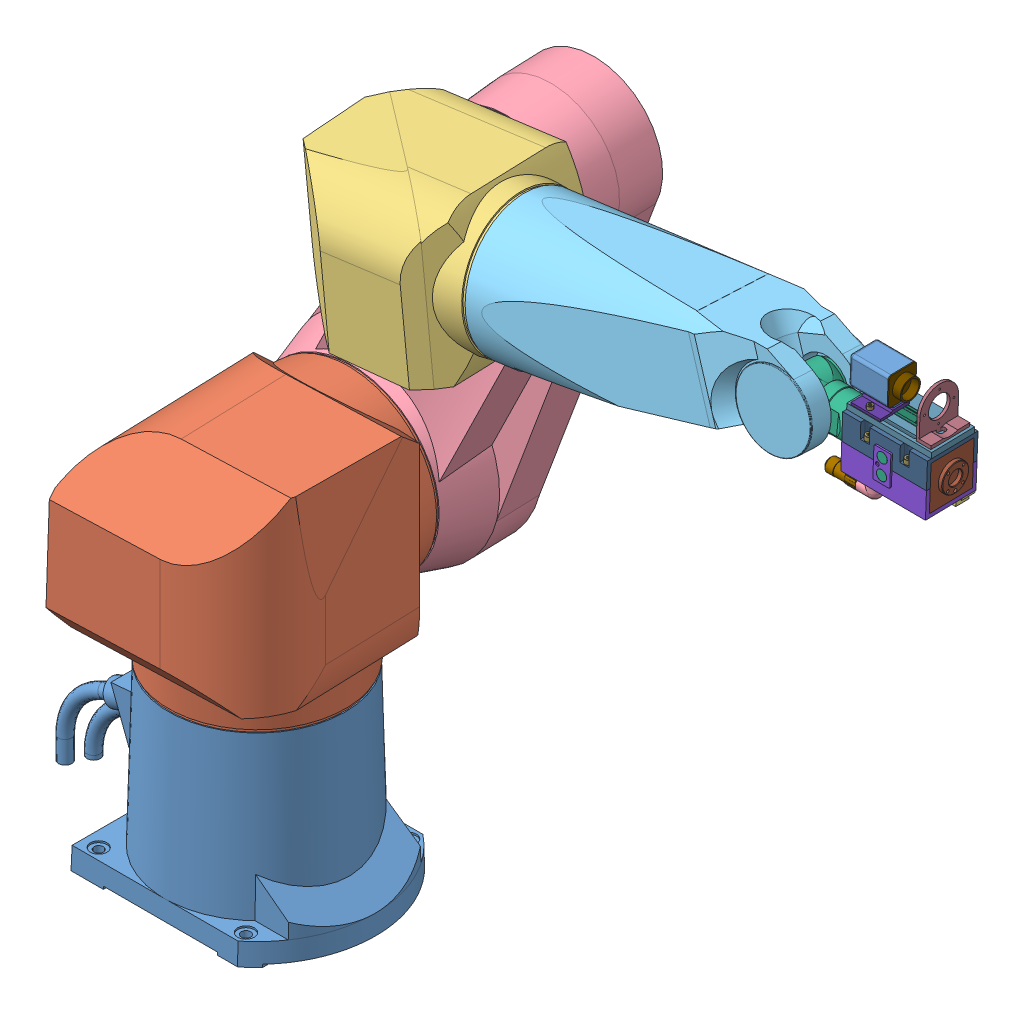
SolidWorks assembly Robot, configuration Default. Lengths in mm.
Overall size (1597.98 1325.39 584.25).
48 component instances, 29 part files, 15 mates.
Components (placement in the parent):
- _MASTER7-1: _MASTER7 [Default] at (48.6878 -5 -52.6772) x (1 0 0) z (0 1 0) size (596.97 337.24 339.66)
- _MASTER6-1: _MASTER6 [Default] at (48.6878 -5.8 -52.6772) x (0.999415 0 -0.034189) z (0 1 0) size (352.5 381 395)
- _MASTER4-1: _MASTER4 [Default] at (358.5721 1107.2932 1073.4366) x (-0.102425 0.994735 0.003504) z (-0.034189 0 -0.999415) size (263.05 319.02 284.97)
- _MASTER3-1: _MASTER3 [Default] at (-189.8314 48.678 -44.5178) x (0.900422 -0.433925 -0.030802) z (0.433671 0.900949 -0.014835) size (372 188.37 936)
- _MASTER-1: _MASTER [Default] at (-811.7526 990.7889 -62.2156) x (0.104669 -0.99202 0.070284) z (0.994153 0.102484 -0.034009) size (240 240 558.7)
- _MASTER1-1: _MASTER1 [Default] at (-820.8951 1231.1583 -80.4296) x (-0.029205 -0.996816 0.0742) z (0.999221 -0.031085 -0.024305) size (96.76 76.5 130.75)
- _MASTER2-1: _MASTER2 [Default] at (-821.8943 1231.1894 -80.4053) x (-0.015425 -0.874658 0.484495) z (0.999221 -0.031085 -0.024305) size (65 65 14)
- Montagem_2-1: Montagem_2 [Default] at (1118.4332 1142.1845 -186.1304) x (0.02452 0.006547 0.999678) z (-0.999221 0.031085 0.024305) size (97 219.55 248.69)
  - Estrutura_bottom-1: Estrutura_bottom [Default] at (58.6974 -11.7987 40.1528) size (94 47 150)
  - Acoplamento_robot_50mm-1: Acoplamento_robot_50mm [Default] at (58.6974 28.2013 25.1528) size (86 86 89.49)
  - Estrutura_top-1: Estrutura_top [Default] at (58.6974 75.2013 40.1528) x (-1 0 0) z (0 0 1) size (94 47 150)
  - robot_fix-2: robot_fix [Default] at (58.6974 28.2013 -94.8472) size (86 86 102.04)
  - Socket Head Cap Screw_ISO-2: Socket Head Cap Screw_ISO [ISO 4762 M8 x 40 --- 28C] at (19.6974 56.2013 -69.8472) x (0 -1 0) z (0 0 1) size (48 13 13)
  - Socket Head Cap Screw_ISO-3: Socket Head Cap Screw_ISO [ISO 4762 M8 x 40 --- 28C] at (97.6974 56.2013 -69.8472) x (0 -1 0) z (0 0 1) size (48 13 13)
  - Socket Head Cap Screw_ISO-4: Socket Head Cap Screw_ISO [ISO 4762 M8 x 40 --- 28C] at (97.6974 56.2013 0.1528) x (0 -1 0) z (0 0 1) size (48 13 13)
  - Socket Head Cap Screw_ISO-5: Socket Head Cap Screw_ISO [ISO 4762 M8 x 40 --- 28C] at (19.6974 56.2013 0.1528) x (0 -1 0) z (0 0 1) size (48 13 13)
  - Acoplamento_garra_50mm-2: Acoplamento_garra_50mm [Default] at (58.6974 28.2013 71.1528) size (60 60 102.04) (hidden)
  - Socket Head Cap Screw_ISO-6: Socket Head Cap Screw_ISO [ISO 4762 M6 x 12 --- 12C] at (72.8395 42.3434 25.1528) x (0 0 1) z (-1 0 0) size (18 10 10)
  - Socket Head Cap Screw_ISO-7: Socket Head Cap Screw_ISO [ISO 4762 M6 x 12 --- 12C] at (44.5553 42.3434 25.1528) x (0 0 1) z (-1 0 0) size (18 10 10)
  - Socket Head Cap Screw_ISO-8: Socket Head Cap Screw_ISO [ISO 4762 M6 x 12 --- 12C] at (72.8395 14.0591 25.1528) x (0 0 1) z (-1 0 0) size (18 10 10)
  - Socket Head Cap Screw_ISO-9: Socket Head Cap Screw_ISO [ISO 4762 M6 x 12 --- 12C] at (44.5553 14.0591 25.1528) x (0 0 1) z (-1 0 0) size (18 10 10)
  - garra_teste-1: garra_teste [Default] at (58.6974 28.2013 -125.8472) size (80 80 89.49) (hidden)
  - Socket Head Cap Screw_ISO-10: Socket Head Cap Screw_ISO [ISO 4762 M6 x 12 --- 12C] at (72.8395 14.0591 -125.8472) x (0 0 1) z (-1 0 0) size (18 10 10) (hidden)
  - Socket Head Cap Screw_ISO-11: Socket Head Cap Screw_ISO [ISO 4762 M6 x 12 --- 12C] at (44.5553 14.0591 -125.8472) x (0 0 1) z (-1 0 0) size (18 10 10) (hidden)
  - Socket Head Cap Screw_ISO-12: Socket Head Cap Screw_ISO [ISO 4762 M6 x 12 --- 12C] at (44.5553 42.3434 -125.8472) x (0 0 1) z (-1 0 0) size (18 10 10) (hidden)
  - Socket Head Cap Screw_ISO-13: Socket Head Cap Screw_ISO [ISO 4762 M6 x 12 --- 12C] at (72.8395 42.3434 -125.8472) x (0 0 1) z (-1 0 0) size (18 10 10) (hidden)
  - Conjunto_visao-1: Conjunto_visao [Default] at (58.3706 75.2013 -34.8472) x (-1 0 0) z (0 0 -1) size (80 85.3 186.38)
    - Apoio_iluminacaoLEDs-1: Apoio_iluminacaoLEDs [Default] at (0 49.3 49) size (72 77.3 83.14)
    - Apoio_sistema_visao-1: Apoio_sistema_visao [Default] at origin size (80 10 150)
    - Calha_deslizante_27mm-1: Calha_deslizante_27mm [Default] at (0 1.5 44) x (1 0 0) z (0 1 0) size (27 114 8.7)
    - Carro_deslizante_27mm-1: Carro_deslizante_27mm [Default] at (0 1.45 -48.7556) x (1 0 0) z (0 1 0) size (23.9 40 5.35)
    - Apoio_camara_27mm-1: Apoio_camara_27mm [Default] at (0 10 -68.7556) x (-1 0 0) z (0 0 -1) size (54 6.9 52)
    - Camara-1: Camara [Default] at (-9.935 38.5559 -34.6236) size (50.8 57.8 84.8)
      - Encaixe_lente-1: Encaixe_lente [Default] at (9.935 10.7441 16.5114) size (50.8 50.8 16.1)
      - Carapaca-1: Carapaca [Default] at (9.935 10.7441 -17.8386) size (50.8 57.8 68.7)
    - Hex Nut GradeC_ISO-1: Hex Nut GradeC_ISO [Hexagon Nut ISO - 4034 - M6 - C] at (-31 6.5 -42.7556) x (1 0 0) z (0 1 0) size (10 11.55 6.1)
    - Socket Head Cap Screw_ISO-2: Socket Head Cap Screw_ISO [ISO 4762 M6 x 12 --- 12C] at (-31 20 -42.7556) x (0 -1 0) z (-0.967727 0 -0.252002) size (18 10 10)
  - Caixa_servo-1: Caixa_servo [Default] at (38.2443 -27.7987 -77.8472) size (25 18 64)
  - Conector_electrico-1: Conector_electrico [Default] at (38.6974 -14.7987 5.1528) x (0 0 1) z (1 0 0) size (52.9 41.5 25.6)
  - Conector_electrico-2: Conector_electrico [Default] at (78.6974 -14.7987 5.1528) x (0 0 1) z (1 0 0) size (52.9 41.5 25.6)
  - Conjunto_sensor-1: Conjunto_sensor [Default] at (95.2021 29.691 -33.63) x (0 -1 0) z (0 0 1) size (66 19.5 41)
    - Placa-1: Placa [Default] at (1.4363 -1.0047 -0.0753) size (50 1.5 25)
    - Sensor-1: Sensor [Default] at (-12.5637 1.4953 -0.0753) size (18 16 18)
    - Sensor-2: Sensor [Default] at (15.4363 1.4953 -0.0753) size (18 16 18)
    - Base-1: Base [Default] at (1.4363 -6.0047 -0.0753) size (55 7.5 30)
    - Tampa-1: Tampa [Default] at (1.4363 1.4953 -0.0753) size (66 13 41)
  - Conectror_electrico_plug-1: Conectror_electrico_plug [Default] at (78.6974 -43.7987 27.3528) x (-0.998562 -0.053604 0) z (0 0 -1) size (25.13 25.13 70.62)
  - Conectror_electrico_plug-2: Conectror_electrico_plug [Default] at (38.6974 -43.7987 27.3528) x (-0.969923 0.243412 0) z (0 0 -1) size (25.13 25.13 70.62)
Mates (geometry in assembly coordinates):
- Coincident1: coincident anti-aligned: plane of _MASTER7-1 through (48.6878 0 -52.6772) normal (0 -1 0); plane of assembly
- Coincident2: coincident anti-aligned: plane of _MASTER7-1 through (48.6878 324.2 -52.6772) normal (0 1 0); plane of _MASTER6-1 through (48.6878 324.2 -52.6772) normal (0 -1 0)
- Concentric1: concentric anti-aligned: circle of _MASTER7-1; circle of _MASTER6-1
- Coincident3: coincident anti-aligned: plane of _MASTER6-1 through (42.8415 544.2 -223.5772) normal (-0.034189 0 -0.999415); plane of _MASTER3-1 through (42.8415 544.2 -223.5772) normal (0.034189 0 0.999415)
- Concentric2: concentric anti-aligned: circle of _MASTER6-1; circle of _MASTER3-1
- Coincident5: coincident anti-aligned: plane of _MASTER4-1 through (313.8877 1107.2932 -232.7993) normal (-0.034189 0 -0.999415); plane of _MASTER3-1 through (313.8877 1107.2932 -232.7993) normal (0.034189 0 0.999415)
- Concentric3: concentric anti-aligned: circle of _MASTER4-1; circle of _MASTER3-1
- Coincident6: coincident anti-aligned: plane of _MASTER4-1 through (488.4008 1124.818 -106.6919) normal (0.994153 0.102484 -0.034009); plane of _MASTER-1 through (378.8905 2327.7358 317.0362) normal (-0.994153 -0.102484 0.034009)
- Concentric4: concentric anti-aligned: circle of _MASTER4-1; circle of _MASTER-1
- Coincident7: coincident anti-aligned: plane of _MASTER1-1 through (1072.6291 1172.2527 -126.4876) normal (0.999221 -0.031085 -0.024305); plane of _MASTER2-1 through (1075.9454 1360.3042 -230.654) normal (-0.999221 0.031085 0.024305)
- Coincident8: coincident aligned: circle of _MASTER1-1; circle of _MASTER2-1
- Width1: width: plane of _MASTER-1 through (976.1044 1170.7814 -184.2447) normal (0.026534 0.073433 0.996947); plane of _MASTER-1 through (979.3415 1179.7403 -62.6171) normal (-0.026534 -0.073433 -0.996947); plane of _MASTER1-1 through (976.708 1172.452 -161.5641) normal (-0.026534 -0.073433 -0.996947); plane of _MASTER1-1 through (978.7379 1178.0697 -85.2977) normal (0.026534 0.073433 0.996947)
- Concentric5: concentric aligned: circle of _MASTER-1; circle of _MASTER1-1
- Concentric12: concentric aligned: cylinder of _MASTER2-1 through (1086.6182 1171.8175 -126.8279) axis (-0.999221 0.031085 0.024305) radius 15.75; cylinder of Montagem_2-1/Acoplamento_robot_50mm-1 through (1086.6182 1171.8175 -126.8279) axis (-0.999221 0.031085 0.024305) radius 12.5
- Coincident12: coincident anti-aligned: plane of _MASTER2-1 through (1080.6228 1172.004 -126.682) normal (0.999221 -0.031085 -0.024305); plane of Montagem_2-1/Acoplamento_robot_50mm-1 through (1078.4054 1131.7623 -166.377) normal (-0.999221 0.031085 0.024305)
